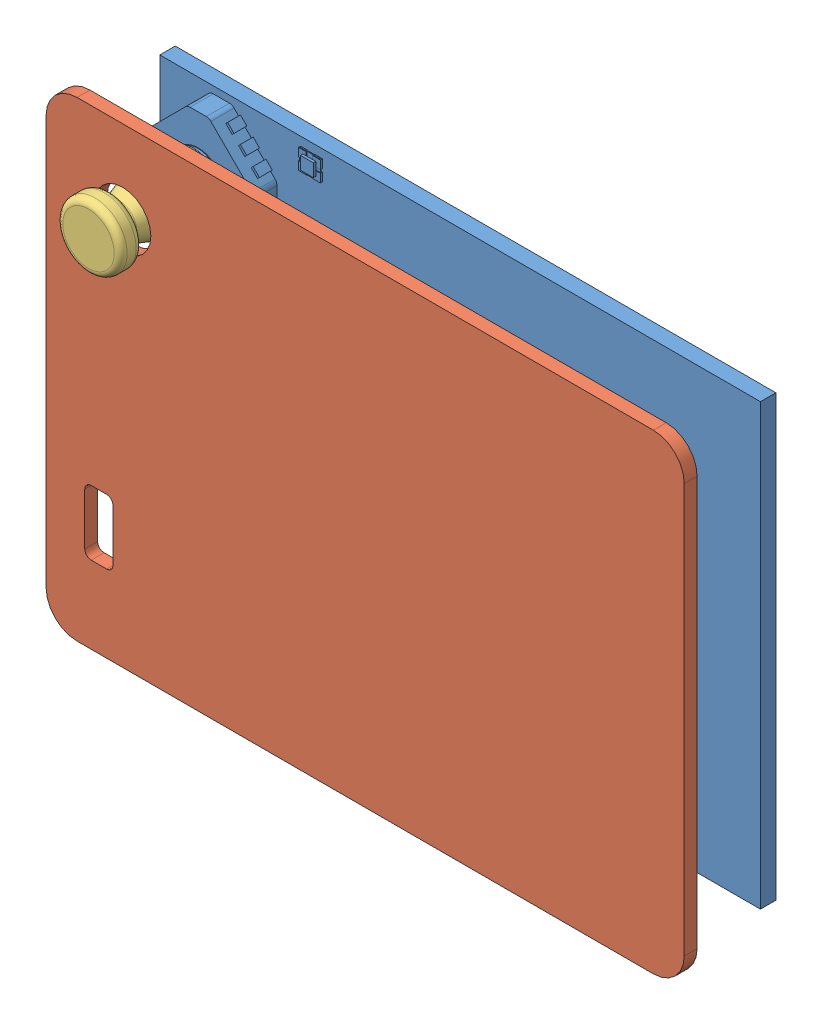
SolidWorks assembly L-ink, configuration 默认. Lengths in mm.
Overall size (49.6 36.6 12.08).
5 component instances, 5 part files, 8 mates.
Components (placement in the parent):
- PCB For InkLCD2-1: PCB For InkLCD2 [默认] at (-25.4458 -63.2724 6.2002) size (46.69 34.16 7.78)
- 外壳 v2.step-1: 外壳 v2.step [默认] at (4.7992 -45.9056 12.8826) size (59 38 11) (hidden)
- 支架 v3.step-1: 支架 v3.step [默认] at (4.4994 -46.2056 12.9711) size (44.74 34.16 7.1) (hidden)
- 面板-1: 面板 [默认] at (4.6992 -45.8056 12.8826) size (49.6 36.6 1)
- 按钮 v3-1: 按钮 v3 [默认] at (-20.6874 -33.9521 16.5002) x (1 0 0) z (0 0 -1) size (5 5 8.3)
Mates (geometry in assembly coordinates):
- 重合1: coincident anti-aligned: plane of PCB For InkLCD2-1 through (21.2394 -63.2724 6.2002) normal (0 0 1); plane of 支架 v3.step-1 through (4.4994 -46.2056 6.2002) normal (0 0 -1)
- 重合2: coincident aligned: plane of PCB For InkLCD2-1 through (21.2394 -63.2724 5.0002) normal (1 0 0); plane of 支架 v3.step-1 through (21.2394 -46.2056 12.9711) normal (1 0 0)
- 重合3: coincident aligned: plane of PCB For InkLCD2-1 through (21.2394 -29.1094 5.0002) normal (0 1 0); plane of 支架 v3.step-1 through (4.4994 -29.1094 12.9711) normal (0 1 0)
- 重合8: coincident anti-aligned: plane of PCB For InkLCD2-1 through (-25.4458 -63.2724 5.0002) normal (0 -1 0); plane of 外壳 v2.step-1 through (4.7992 -63.2724 12.8826) normal (0 1 0)
- 重合9: coincident anti-aligned: plane of PCB For InkLCD2-1 through (-25.4458 -29.1094 5.0002) normal (-1 0 0); plane of 外壳 v2.step-1 through (-25.4458 -45.9056 12.8826) normal (1 0 0)
- 重合13: coincident anti-aligned: plane of 外壳 v2.step-1 through (-26.6008 -45.9056 12.8826) normal (1 0 0); plane of 面板-1 through (-26.6008 -45.8056 13.8826) normal (-1 0 0)
- 重合14: coincident anti-aligned: plane of 外壳 v2.step-1 through (4.7992 -27.5056 12.8826) normal (0 -1 0); plane of 面板-1 through (4.6992 -27.5056 13.8826) normal (0 1 0)
- 重合15: coincident anti-aligned: plane of 外壳 v2.step-1 through (4.7992 -45.9056 12.8826) normal (0 0 1); plane of 面板-1 through (4.6992 -45.8056 12.8826) normal (0 0 -1)
